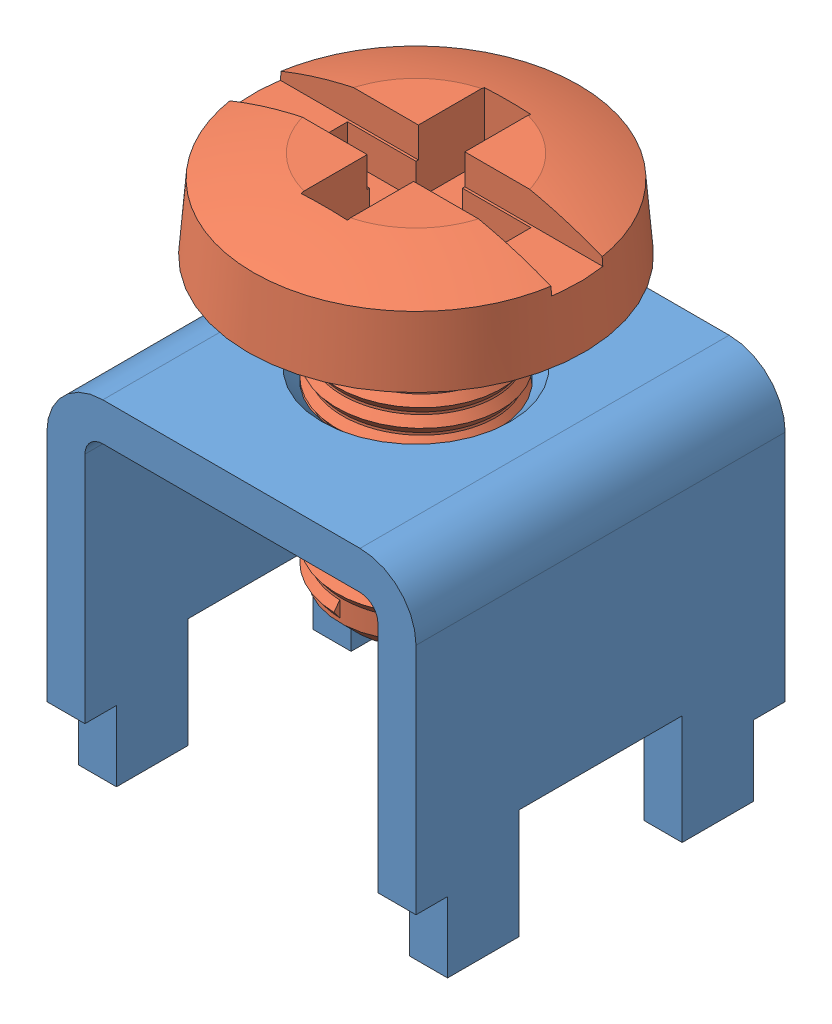
SolidWorks assembly ScrewTerminalAssembly, configuration Default. Lengths in mm.
Overall size (7.87 11.69 7.87).
2 component instances, 2 part files, 0 mates.
Components (placement in the parent):
- ScrewTerminalBase-1: ScrewTerminalBase [Default] at (3.4868 6.6312 8.3972) size (7.87 7.68 7.87)
- ScrewTerminalScrew-1: ScrewTerminalScrew [Default] at (3.5041 -1.1314 8.5263) x (0.998152 0 -0.060771) z (0.060771 0 0.998152) size (7.16 8.3 7.16)
